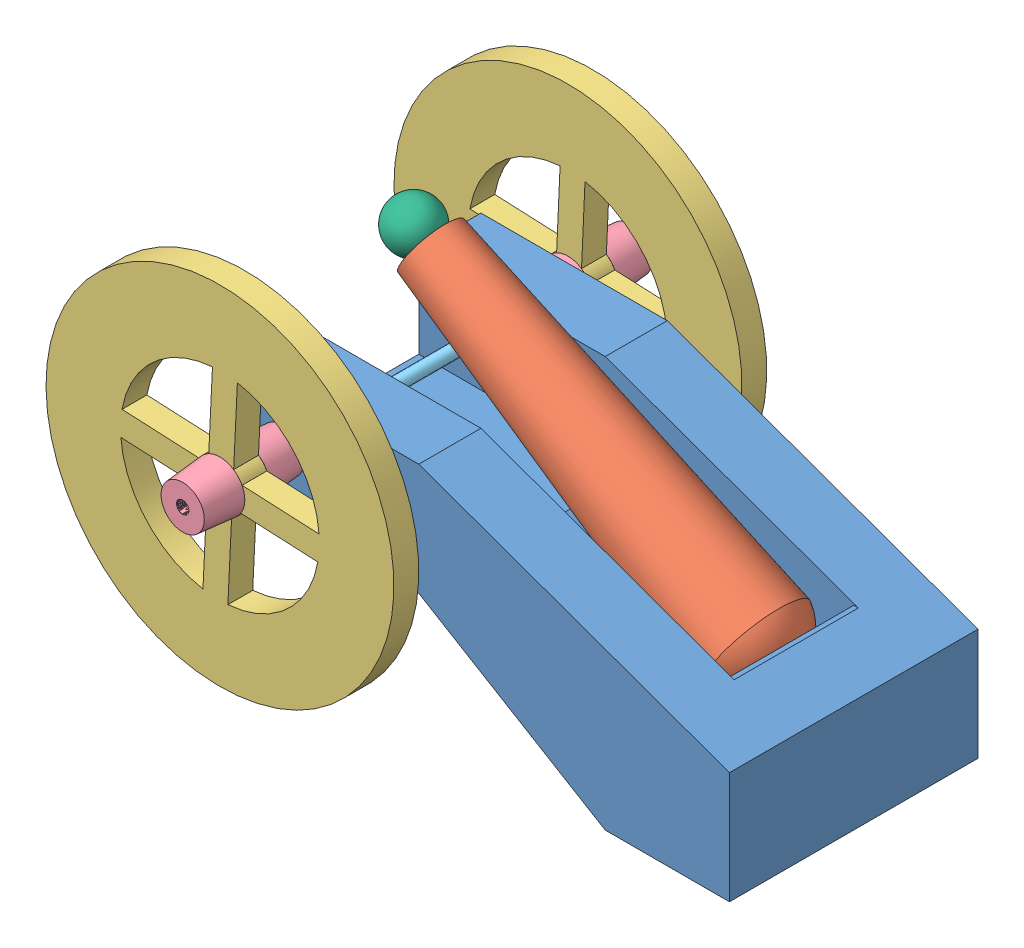
SolidWorks assembly ASSEMBLY, configuration Default. Lengths in mm.
Overall size (643.35 373.47 457.2).
12 component instances, 6 part files, 8 mates.
Components (placement in the parent):
- BASE-1: BASE [Default] at origin size (508 228.6 254)
- LAUNCHER-1: LAUNCHER [Default] at (150.5141 -3.1183 124.0202) x (-0.402283 -0.722249 -0.562605) z (-0.872719 0.488215 -0.002724) size (101.6 101.6 419.1)
- ENTIRE WHEEL-1: ENTIRE WHEEL [Default] at (-203.2 57.15 317.5) x (0.998841 -0.04813 0) z (0 0 1) size (355.6 355.6 101.6)
  - Wheel-1: Wheel [Default] at origin size (355.6 355.6 25.68)
  - WHEEL CAP-1: WHEEL CAP [Default] x (0.837507 0.546426 0) z (0 0 1) size (50.8 50.8 38.1)
  - WHEEL CAP-2: WHEEL CAP [Default] at (0 0 -25.4) x (-0.52724 -0.849716 0) z (0 0 -1) size (50.8 50.8 38.1)
- ENTIRE WHEEL-2: ENTIRE WHEEL [Default] at (-203.2 57.15 -38.1) x (0.999 -0.044706 0) z (0 0 1) size (355.6 355.6 101.6)
  - Wheel-1: Wheel [Default] at origin size (355.6 355.6 25.68)
  - WHEEL CAP-1: WHEEL CAP [Default] x (0.837507 0.546426 0) z (0 0 1) size (50.8 50.8 38.1)
  - WHEEL CAP-2: WHEEL CAP [Default] at (0 0 -25.4) x (-0.52724 -0.849716 0) z (0 0 -1) size (50.8 50.8 38.1)
- AXLE-1: AXLE [Default] at (-203.2 57.15 -78.3031) x (0.988665 -0.150137 0) z (0 0 1) size (12.7 12.7 381)
- CANNON BALL-1: CANNON BALL [Default] at (-199.7255 192.8122 122.927) x (0.279398 -0.231975 0.931732) z (0.184342 -0.939366 -0.289154) size (50.8 50.8 50.8)
Mates (geometry in assembly coordinates):
- Concentric1: concentric: circle of BASE-1; circle of ENTIRE WHEEL-1/WHEEL CAP-2
- Concentric2: concentric: circle of BASE-1; circle of ENTIRE WHEEL-2/WHEEL CAP-1
- Concentric3: concentric: circle of BASE-1; circle of AXLE-1
- Tangent9: tangent: circle of BASE-1; plane of ENTIRE WHEEL-2/WHEEL CAP-1 through (-203.2 57.15 0) normal (0 0 1)
- Tangent11: tangent: circle of BASE-1; plane of ENTIRE WHEEL-1/WHEEL CAP-2 through (-203.2 57.15 254) normal (0 0 -1)
- Tangent12: tangent: circle of LAUNCHER-1; sphere of CANNON BALL-1
- Coincident6: coincident: circle of LAUNCHER-1; sphere of CANNON BALL-1
- Tangent13: tangent: plane of BASE-1 through (190.5 0 0) normal (-1 0 0); sphere of LAUNCHER-1
